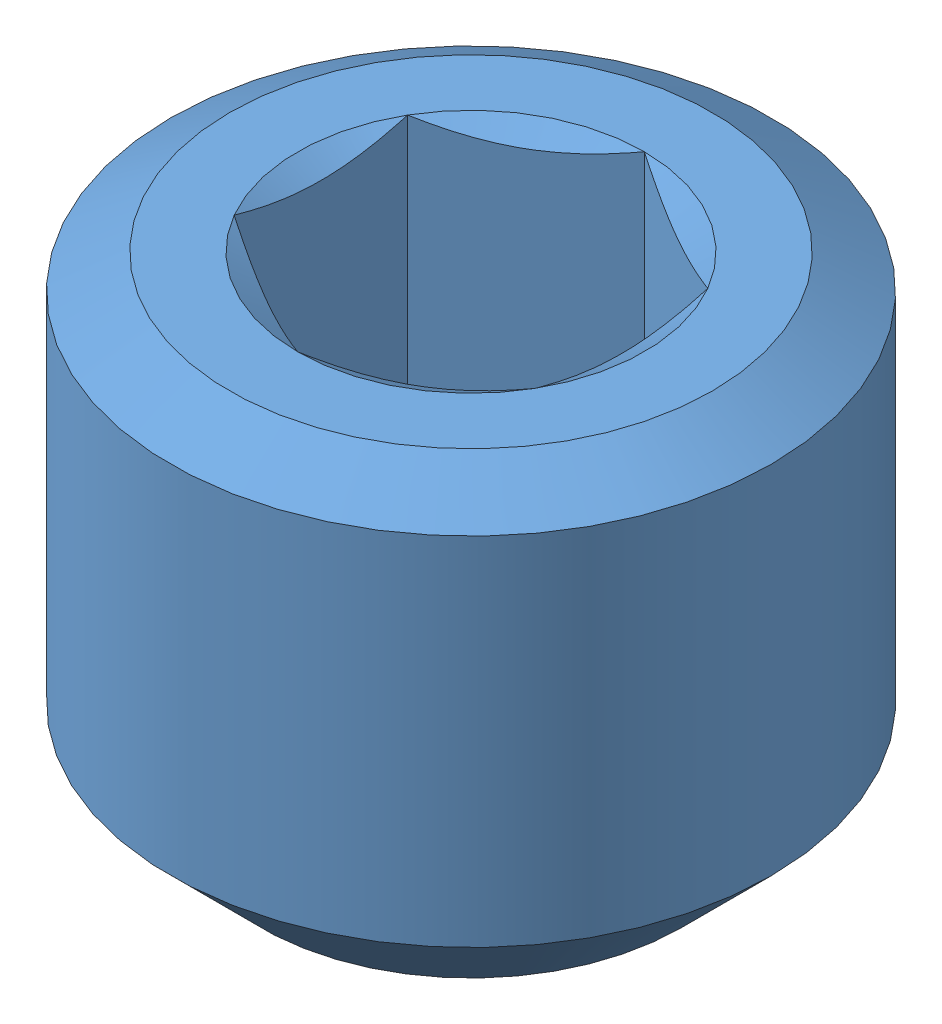
SolidWorks assembly GEABG1_0_14_8_K_6_35, configuration Default. Lengths in mm.
Overall size (29.3 14.93 22.5).
4 component instances, 3 part files, 0 mates.
Components (placement in the parent):
- GEABS0_8_15_7_K_5-1: GEABS0_8_15_7_K_5 [Default] x (0 0 -1) z (1 0 0) size (20 13.6 13.6)
  - GEABS0_8_15_7_5_1-1: GEABS0_8_15_7_5_1 [Default] x (0 0 -1) z (1 0 0) size (13.6 13.6 20)
  - Hexagon_socket_set_screw_with_flat_point_DIN_913___M3x4-1: Hexagon_socket_set_screw_with_flat_point_DIN_913___M3x4 [Default] at (17 6.8 0) x (0 -1 0) z (0 0 1) size (4 3 3)
- Hexagon_socket_set_screw_with_flat_point_DIN_913___M5x4-1: Hexagon_socket_set_screw_with_flat_point_DIN_913___M5x4 [Default] at (20 8 0) x (0 -1 0) z (0 0 1) size (4.13 5 5)
